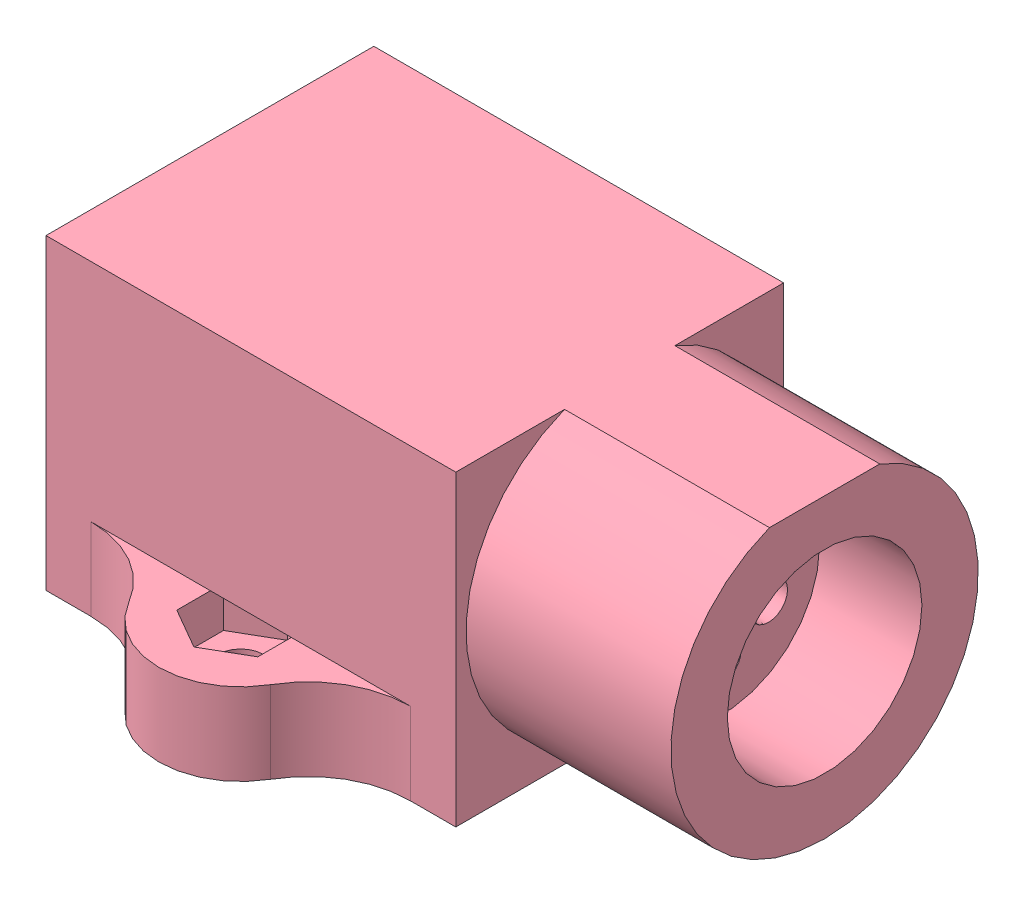
SolidWorks assembly pressure_board, configuration Default. Lengths in mm.
Overall size (30 16 25).
6 component instances, 4 part files, 10 mates.
Components (placement in the parent):
- sdp3x-1: sdp3x [Default] at (4.5 0 3) size (8.5 4.4 5.5)
- sdp3x-2: sdp3x [Default] at (4.5 0 -3) x (-1 0 0) z (0 0 -1) size (8.5 4.4 5.5)
- sdp3x-3: sdp3x [Default] at (-4.5 0 3) size (8.5 4.4 5.5)
- static_pressure_connector-1: static_pressure_connector [Default] at (-4.5 0 -3) size (8 6.1 9.55)
- PCB^pressure_board-1: PCB^pressure_board [Default] at origin size (18 1 22) (virtual)
- Part2^pressure_board-1: Part2^pressure_board [Default] at origin size (30 15 25) (virtual)
Mates (geometry in assembly coordinates):
- Coincident1: coincident aligned: plane of sdp3x-1 through (4.5 0 3) normal (0 1 0); plane of assembly through (0 0 0) normal (0 1 0)
- Distance1: distance = 3 mm: plane of assembly through (0 0 0) normal (0 0 1); point of sdp3x-1
- Distance2: distance = 4.5 mm: point of sdp3x-1; plane of assembly
- Coincident4: coincident aligned: plane of static_pressure_connector-1 through (-4.5 0 -3) normal (0 1 0); plane of assembly through (0 0 0) normal (0 1 0)
- Distance3: distance = 3 mm: point of static_pressure_connector-1; plane of assembly
- Distance4: distance = 4.5 mm: point of static_pressure_connector-1; plane of assembly
- Coincident8: coordinate: unknown of ?
- Coincident11: coordinate: unknown of ?
- Coincident12: coincident anti-aligned: plane of Part2^pressure_board-1 through (15 2 0) normal (1 0 0); plane of ? through (15 8 0) normal (-1 0 0)
- Concentric1: concentric anti-aligned: cylinder of Part2^pressure_board-1 through (-4.435 8 0) axis (1 0 0) radius 4.75; cylinder of ? through (215 8 0) axis (-1 0 0) radius 4.75
